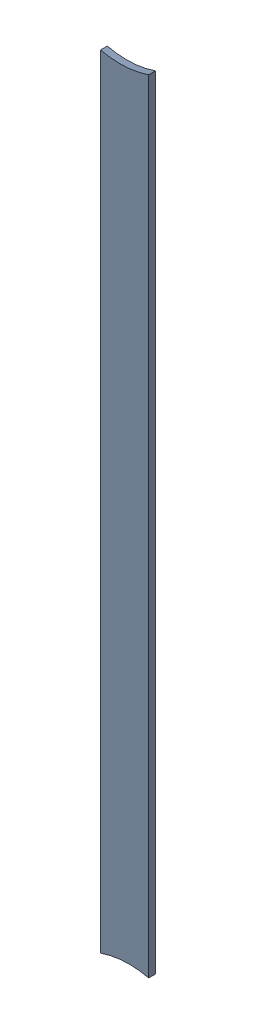
SolidWorks assembly Track (20.597mm,43.423mm)(20.597mm,48.364mm) on Top Layer, configuration Predeterminado. Lengths in mm.
Overall size (0.25 4.14 0.04).
2 component instances, 1 part files, 0 mates.
Components (placement in the parent):
- Track (20.597mm,43.423mm)(20.597mm,48.364mm) on Top Layer-1-1: Track (20.597mm,43.423mm)(20.597mm,48.364mm) on Top Layer-1 [Predeterminado] at (-68.317 -44.187 -0.0457) size (0.25 4.14 0.04)
  - Track (20.597mm,43.423mm)(20.597mm,48.364mm) on Top Layer-Part-1-1: Track (20.597mm,43.423mm)(20.597mm,48.364mm) on Top Layer-Part-1 [Predeterminado] at origin size (0.25 4.14 0.04)
